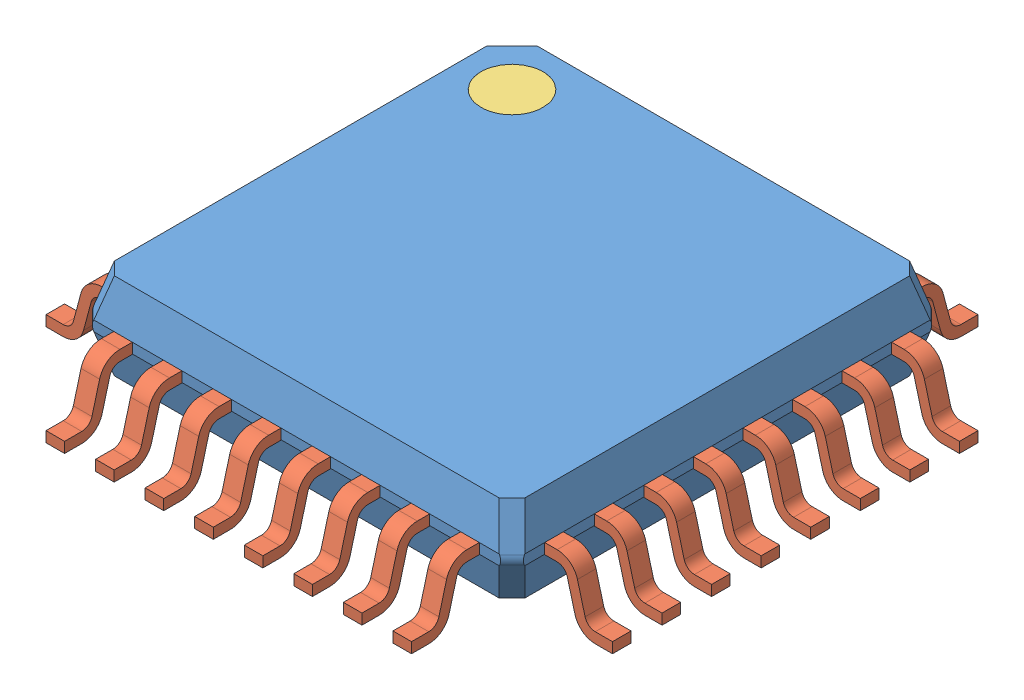
SolidWorks assembly User Library-LQFP32-2, configuration Default. Lengths in mm.
Overall size (9.14 1.63 9.14).
34 component instances, 3 part files, 0 mates.
Components (placement in the parent):
- User Library-LQFP32-2_case-1: User Library-LQFP32-2_case [Default] at (0 0.92 0) size (6.96 1.4 6.96)
- User Library-LQFP32-2_pin-1: User Library-LQFP32-2_pin [Default] at (-2.8 0.8321 3.478) size (0.3 1.01 1.09)
- User Library-LQFP32-2_pin-2: User Library-LQFP32-2_pin [Default] at (-2 0.8321 3.478) size (0.3 1.01 1.09)
- User Library-LQFP32-2_pin-3: User Library-LQFP32-2_pin [Default] at (-1.2 0.8321 3.478) size (0.3 1.01 1.09)
- User Library-LQFP32-2_pin-4: User Library-LQFP32-2_pin [Default] at (-0.4 0.8321 3.478) size (0.3 1.01 1.09)
- User Library-LQFP32-2_pin-5: User Library-LQFP32-2_pin [Default] at (0.4 0.8321 3.478) size (0.3 1.01 1.09)
- User Library-LQFP32-2_pin-6: User Library-LQFP32-2_pin [Default] at (1.2 0.8321 3.478) size (0.3 1.01 1.09)
- User Library-LQFP32-2_pin-7: User Library-LQFP32-2_pin [Default] at (2 0.8321 3.478) size (0.3 1.01 1.09)
- User Library-LQFP32-2_pin-8: User Library-LQFP32-2_pin [Default] at (2.8 0.8321 3.478) size (0.3 1.01 1.09)
- User Library-LQFP32-2_pin-9: User Library-LQFP32-2_pin [Default] at (3.478 0.8321 2.8) x (0 0 -1) z (1 0 0) size (0.3 1.01 1.09)
- User Library-LQFP32-2_pin-10: User Library-LQFP32-2_pin [Default] at (3.478 0.8321 2) x (0 0 -1) z (1 0 0) size (0.3 1.01 1.09)
- User Library-LQFP32-2_pin-11: User Library-LQFP32-2_pin [Default] at (3.478 0.8321 1.2) x (0 0 -1) z (1 0 0) size (0.3 1.01 1.09)
- User Library-LQFP32-2_pin-12: User Library-LQFP32-2_pin [Default] at (3.478 0.8321 0.4) x (0 0 -1) z (1 0 0) size (0.3 1.01 1.09)
- User Library-LQFP32-2_pin-13: User Library-LQFP32-2_pin [Default] at (3.478 0.8321 -0.4) x (0 0 -1) z (1 0 0) size (0.3 1.01 1.09)
- User Library-LQFP32-2_pin-14: User Library-LQFP32-2_pin [Default] at (3.478 0.8321 -1.2) x (0 0 -1) z (1 0 0) size (0.3 1.01 1.09)
- User Library-LQFP32-2_pin-15: User Library-LQFP32-2_pin [Default] at (3.478 0.8321 -2) x (0 0 -1) z (1 0 0) size (0.3 1.01 1.09)
- User Library-LQFP32-2_pin-16: User Library-LQFP32-2_pin [Default] at (3.478 0.8321 -2.8) x (0 0 -1) z (1 0 0) size (0.3 1.01 1.09)
- User Library-LQFP32-2_pin-17: User Library-LQFP32-2_pin [Default] at (2.8 0.8321 -3.478) x (-1 0 0) z (0 0 -1) size (0.3 1.01 1.09)
- User Library-LQFP32-2_pin-18: User Library-LQFP32-2_pin [Default] at (2 0.8321 -3.478) x (-1 0 0) z (0 0 -1) size (0.3 1.01 1.09)
- User Library-LQFP32-2_pin-19: User Library-LQFP32-2_pin [Default] at (1.2 0.8321 -3.478) x (-1 0 0) z (0 0 -1) size (0.3 1.01 1.09)
- User Library-LQFP32-2_pin-20: User Library-LQFP32-2_pin [Default] at (0.4 0.8321 -3.478) x (-1 0 0) z (0 0 -1) size (0.3 1.01 1.09)
- User Library-LQFP32-2_pin-21: User Library-LQFP32-2_pin [Default] at (-0.4 0.8321 -3.478) x (-1 0 0) z (0 0 -1) size (0.3 1.01 1.09)
- User Library-LQFP32-2_pin-22: User Library-LQFP32-2_pin [Default] at (-1.2 0.8321 -3.478) x (-1 0 0) z (0 0 -1) size (0.3 1.01 1.09)
- User Library-LQFP32-2_pin-23: User Library-LQFP32-2_pin [Default] at (-2 0.8321 -3.478) x (-1 0 0) z (0 0 -1) size (0.3 1.01 1.09)
- User Library-LQFP32-2_pin-24: User Library-LQFP32-2_pin [Default] at (-2.8 0.8321 -3.478) x (-1 0 0) z (0 0 -1) size (0.3 1.01 1.09)
- User Library-LQFP32-2_pin-25: User Library-LQFP32-2_pin [Default] at (-3.478 0.8321 -2.8) x (0 0 1) z (-1 0 0) size (0.3 1.01 1.09)
- User Library-LQFP32-2_pin-26: User Library-LQFP32-2_pin [Default] at (-3.478 0.8321 -2) x (0 0 1) z (-1 0 0) size (0.3 1.01 1.09)
- User Library-LQFP32-2_pin-27: User Library-LQFP32-2_pin [Default] at (-3.478 0.8321 -1.2) x (0 0 1) z (-1 0 0) size (0.3 1.01 1.09)
- User Library-LQFP32-2_pin-28: User Library-LQFP32-2_pin [Default] at (-3.478 0.8321 -0.4) x (0 0 1) z (-1 0 0) size (0.3 1.01 1.09)
- User Library-LQFP32-2_pin-29: User Library-LQFP32-2_pin [Default] at (-3.478 0.8321 0.4) x (0 0 1) z (-1 0 0) size (0.3 1.01 1.09)
- User Library-LQFP32-2_pin-30: User Library-LQFP32-2_pin [Default] at (-3.478 0.8321 1.2) x (0 0 1) z (-1 0 0) size (0.3 1.01 1.09)
- User Library-LQFP32-2_pin-31: User Library-LQFP32-2_pin [Default] at (-3.478 0.8321 2) x (0 0 1) z (-1 0 0) size (0.3 1.01 1.09)
- User Library-LQFP32-2_pin-32: User Library-LQFP32-2_pin [Default] at (-3.478 0.8321 2.8) x (0 0 1) z (-1 0 0) size (0.3 1.01 1.09)
- User Library-LQFP32-2_circle-1: User Library-LQFP32-2_circle [Default] at (-2.5 1.52 -2.5) size (1 0.1 1)
